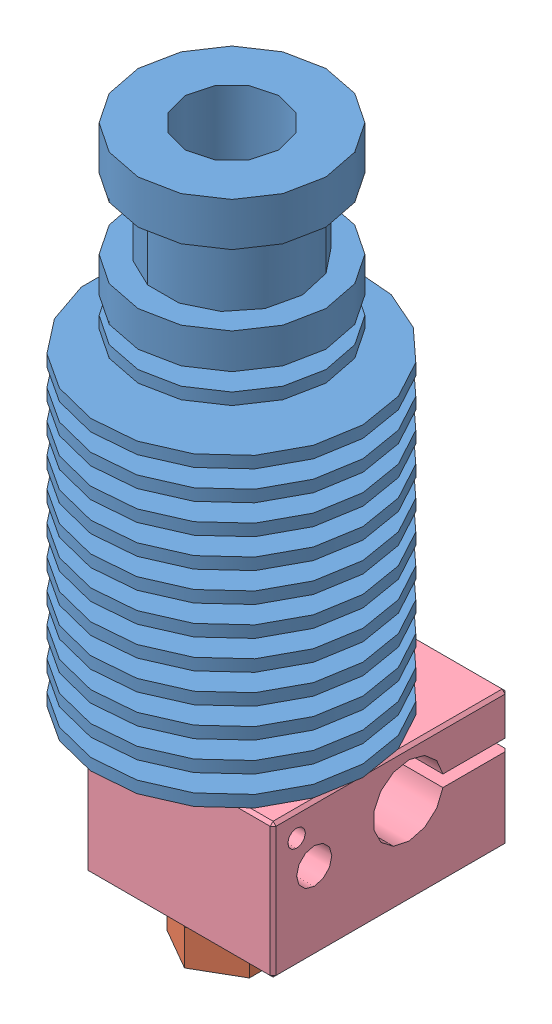
SolidWorks assembly ED3V6 v3, configuration Predeterminado. Lengths in mm.
Overall size (22.3 62.3 26.65).
4 component instances, 4 part files, 0 mates.
Components (placement in the parent):
- HEATSINK-1: HEATSINK [Predeterminado] at (-10.5 -30.2 -54.8237) x (0 0 -1) z (1 0 0) size (22.3 42.7 22.3)
- NOZZLE 0-1: NOZZLE 0 [Predeterminado] at (-10.5 -47.8 -54.8237) x (-0.000004 0 -1) z (1 0 -0.000004) size (8.08 12.5 7)
- HEATBRICK-1: HEATBRICK [Predeterminado] at (-10.5 -37.3 -54.8237) x (-0.229608 0 -0.973283) z (0.973283 0 -0.229608) size (7 21.9 7)
- HEATERBLOCK-1: HEATERBLOCK [Predeterminado] at (-10.5 -33 -60.3237) x (0.000004 0 1) z (1 0 -0.000004) size (20 11.5 16)
